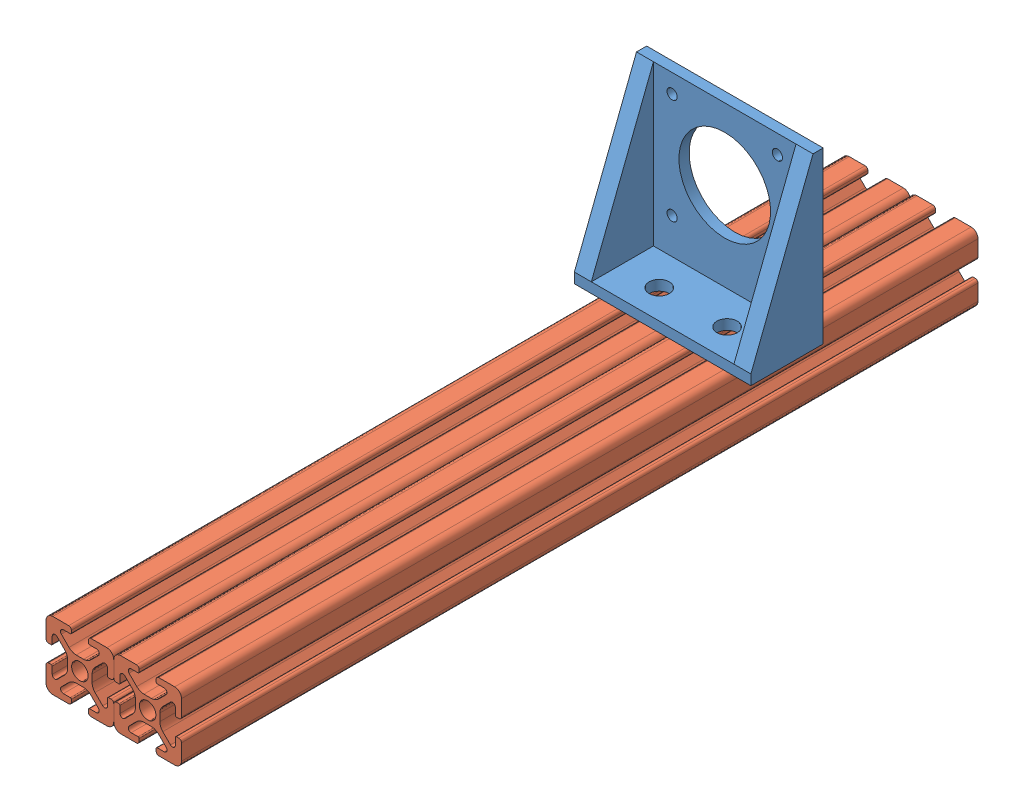
SolidWorks assembly Assem2, configuration Default. Lengths in mm.
Overall size (52 69.96 234.6).
3 component instances, 2 part files, 6 mates.
Components (placement in the parent):
- steppermountlonger-1: steppermountlonger [Default] at (-154.6487 8.7045 170.7082) x (1 0 0) z (0 1 0) size (52 21.3 50)
- AluminumExtrusion-1: AluminumExtrusion [9inches] at (-66.4839 -1.2755 57.5077) size (19.96 19.96 234.6)
- AluminumExtrusion-2: AluminumExtrusion [9inches] at (-46.5239 -1.2755 57.5077) size (19.96 19.96 234.6)
Mates (geometry in assembly coordinates):
- Coincident1: coincident anti-aligned: plane of AluminumExtrusion-1 through (-56.5039 6.6979 174.8077) normal (1 0 0); plane of AluminumExtrusion-2 through (-56.5039 6.6979 174.8077) normal (-1 0 0)
- Coincident2: coincident aligned: plane of AluminumExtrusion-1 through (-58.5105 8.7045 174.8077) normal (0 1 0); plane of AluminumExtrusion-2 through (-54.4973 8.7045 174.8077) normal (0 1 0)
- Coincident3: coincident aligned: plane of AluminumExtrusion-1 through (-67.5724 5.3047 174.8077) normal (0 0 1); plane of AluminumExtrusion-2 through (-47.6124 5.3047 174.8077) normal (0 0 1)
- Coincident4: coincident: plane of steppermountlonger-1 through (-77.4639 8.7045 -8.1578) normal (0 -1 0); plane of AluminumExtrusion-1 through (-74.4573 8.7045 174.8077) normal (0 1 0)
- Parallel1: parallel: plane of steppermountlonger-1 through (-77.4639 11.7045 -8.1578) normal (0 0 -1); plane of AluminumExtrusion-1 through (-67.5724 5.3047 -59.7923) normal (0 0 -1)
- Distance1: distance = 1.04 mm anti-aligned: plane of steppermountlonger-1 through (-77.5039 8.7045 13.1422) normal (1 0 0); plane of AluminumExtrusion-1 through (-76.4639 6.6979 174.8077) normal (-1 0 0)
